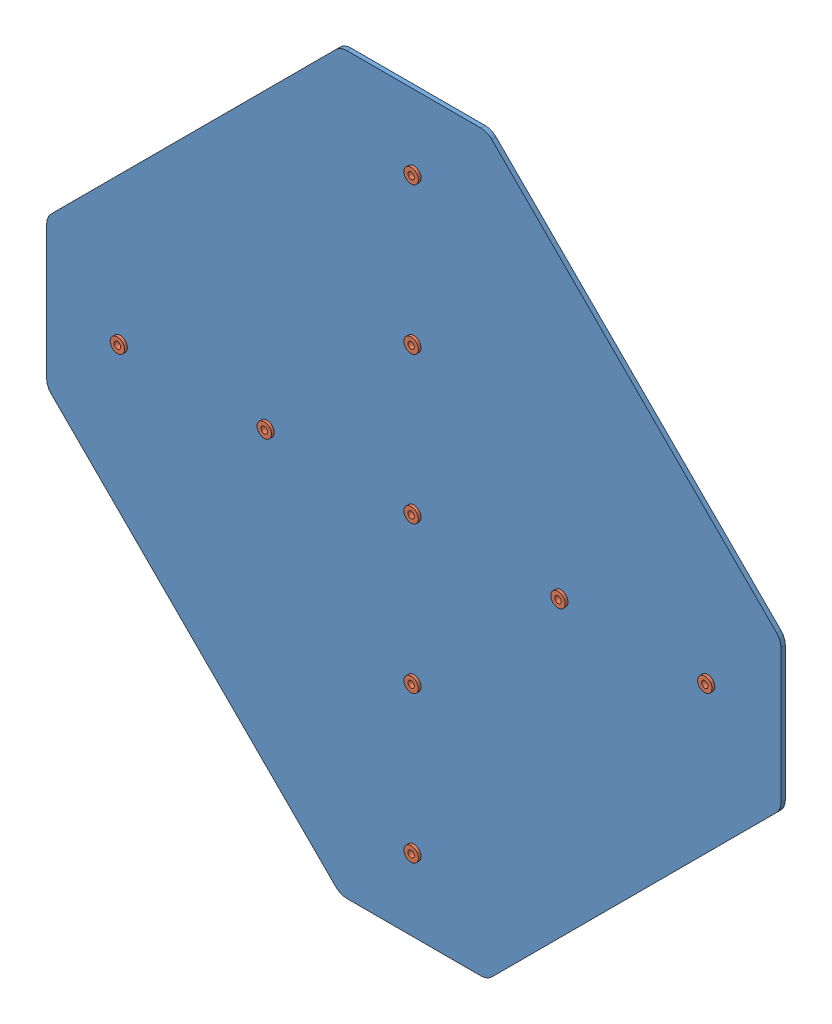
SolidWorks assembly cross_w_rivets, configuration Default. Lengths in mm.
Overall size (269.88 269.88 7).
10 component instances, 2 part files, 18 mates.
Components (placement in the parent):
- 2inch_plus170927-1: 2inch_plus170927 [Default] at (3.2394 8.1132 -8.0151) size (269.88 269.88 1.59)
- 0.3125 rivet170927-2: 0.3125 rivet170927 [Default] at (-50.7356 8.1132 -6.4276) x (0.987351 0.158553 0) z (0.158553 -0.987351 0) size (5.3 7 5.3)
- 0.3125 rivet170927-3: 0.3125 rivet170927 [Default] at (3.2394 62.0882 -6.4276) x (0.959125 0.282984 0) z (0.282984 -0.959125 0) size (5.3 7 5.3)
- 0.3125 rivet170927-4: 0.3125 rivet170927 [Default] at (3.2394 116.0632 -6.4276) x (0.928571 0.371154 0) z (0.371154 -0.928571 0) size (5.3 7 5.3)
- 0.3125 rivet170927-5: 0.3125 rivet170927 [Default] at (3.2394 8.1132 -6.4276) x (0.906989 0.421154 0) z (0.421154 -0.906989 0) size (5.3 7 5.3)
- 0.3125 rivet170927-6: 0.3125 rivet170927 [Default] at (3.2394 -45.8618 -6.4276) x (0.902849 0.429957 0) z (0.429957 -0.902849 0) size (5.3 7 5.3)
- 0.3125 rivet170927-7: 0.3125 rivet170927 [Default] at (3.2394 -99.8368 -6.4276) x (0.919615 0.39282 0) z (0.39282 -0.919615 0) size (5.3 7 5.3)
- 0.3125 rivet170927-8: 0.3125 rivet170927 [Default] at (57.2144 8.1132 -6.4276) x (0.952324 0.305088 0) z (0.305088 -0.952324 0) size (5.3 7 5.3)
- 0.3125 rivet170927-9: 0.3125 rivet170927 [Default] at (111.1894 8.1132 -6.4276) x (0.985697 0.168526 0) z (0.168526 -0.985697 0) size (5.3 7 5.3)
- 0.3125 rivet170927-11: 0.3125 rivet170927 [Default] at (-104.7106 8.1132 -6.4276) x (0.949722 0.313094 0) z (0.313094 -0.949722 0) size (5.3 7 5.3)
Mates (geometry in assembly coordinates):
- Coincident2: coincident anti-aligned: plane of 2inch_plus170927-1 through (132.6207 -16.5729 -6.4276) normal (0 0 1); plane of 0.3125 rivet170927-2 through (-52.3647 7.8516 -6.4276) normal (0 0 -1)
- Concentric2: concentric anti-aligned: circle of 2inch_plus170927-1; circle of 0.3125 rivet170927-2
- Coincident3: coincident anti-aligned: plane of 2inch_plus170927-1 through (132.6207 -16.5729 -6.4276) normal (0 0 1); plane of 0.3125 rivet170927-3 through (1.6569 61.6212 -6.4276) normal (0 0 -1)
- Concentric3: concentric anti-aligned: circle of 2inch_plus170927-1; circle of 0.3125 rivet170927-3
- Coincident4: coincident anti-aligned: plane of 2inch_plus170927-1 through (132.6207 -16.5729 -6.4276) normal (0 0 1); plane of 0.3125 rivet170927-4 through (1.7073 115.4508 -6.4276) normal (0 0 -1)
- Concentric4: concentric anti-aligned: circle of 2inch_plus170927-1; circle of 0.3125 rivet170927-4
- Coincident5: coincident anti-aligned: plane of 2inch_plus170927-1 through (132.6207 -16.5729 -6.4276) normal (0 0 1); plane of 0.3125 rivet170927-5 through (1.7429 7.4183 -6.4276) normal (0 0 -1)
- Concentric5: concentric anti-aligned: circle of 2inch_plus170927-1; circle of 0.3125 rivet170927-5
- Coincident6: coincident anti-aligned: plane of 2inch_plus170927-1 through (132.6207 -16.5729 -6.4276) normal (0 0 1); plane of 0.3125 rivet170927-6 through (1.7497 -46.5713 -6.4276) normal (0 0 -1)
- Concentric6: concentric anti-aligned: circle of 2inch_plus170927-1; circle of 0.3125 rivet170927-6
- Coincident7: coincident anti-aligned: plane of 2inch_plus170927-1 through (132.6207 -16.5729 -6.4276) normal (0 0 1); plane of 0.3125 rivet170927-7 through (1.7221 -100.485 -6.4276) normal (0 0 -1)
- Concentric7: concentric anti-aligned: circle of 2inch_plus170927-1; circle of 0.3125 rivet170927-7
- Coincident8: coincident anti-aligned: plane of 2inch_plus170927-1 through (132.6207 -16.5729 -6.4276) normal (0 0 1); plane of 0.3125 rivet170927-8 through (55.6431 7.6098 -6.4276) normal (0 0 -1)
- Concentric8: concentric anti-aligned: circle of 2inch_plus170927-1; circle of 0.3125 rivet170927-8
- Coincident9: coincident anti-aligned: plane of 2inch_plus170927-1 through (132.6207 -16.5729 -6.4276) normal (0 0 1); plane of 0.3125 rivet170927-9 through (109.563 7.8351 -6.4276) normal (0 0 -1)
- Concentric9: concentric anti-aligned: circle of 2inch_plus170927-1; circle of 0.3125 rivet170927-9
- Coincident11: coincident anti-aligned: plane of 2inch_plus170927-1 through (132.6207 -16.5729 -6.4276) normal (0 0 1); plane of 0.3125 rivet170927-11 through (-106.2776 7.5966 -6.4276) normal (0 0 -1)
- Concentric10: concentric anti-aligned: circle of 2inch_plus170927-1; circle of 0.3125 rivet170927-11
